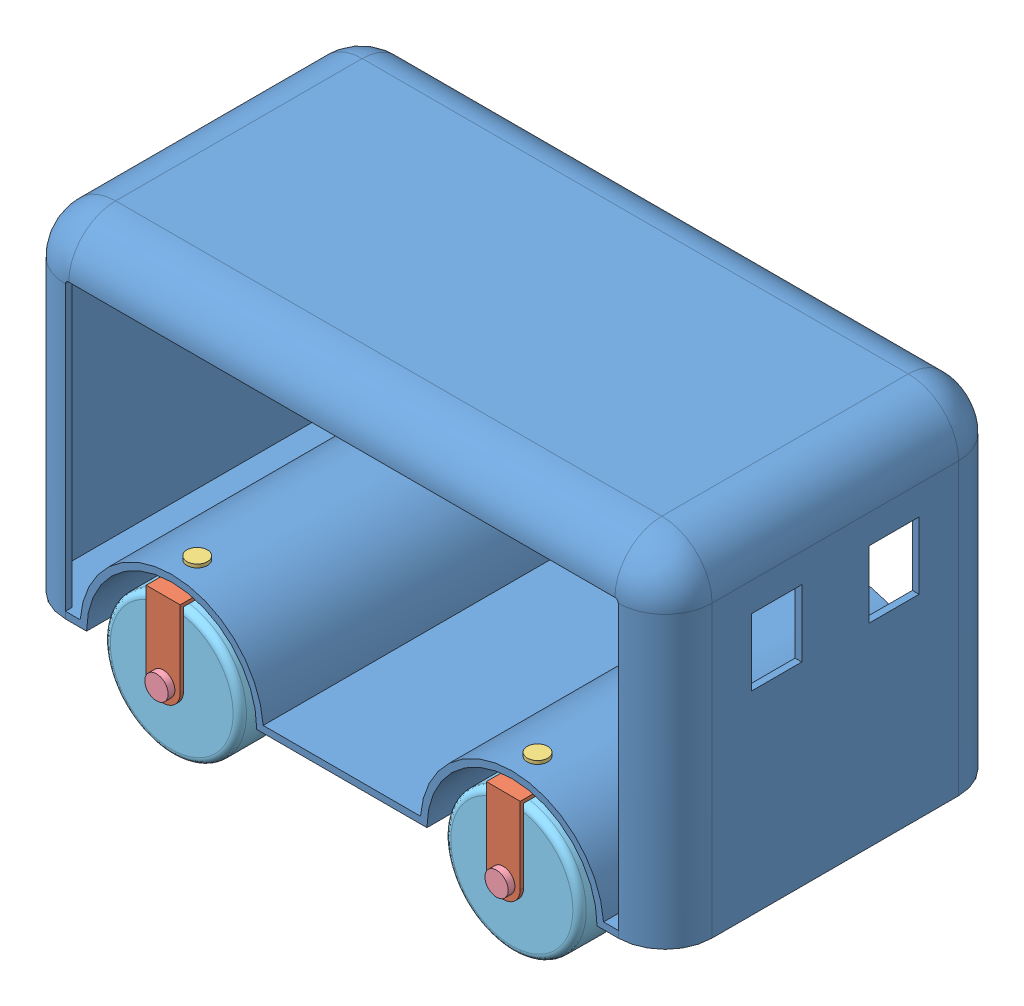
SolidWorks assembly FinalAssem4, configuration Default. Lengths in mm.
Overall size (965.2 647.74 554.88).
21 component instances, 5 part files, 18 mates.
Components (placement in the parent):
- BODY-1: BODY [Default] at (355.0397 333.1063 686.9716) size (965.2 508 508)
- Assem1-1: Assem1 [Default] at (150.2541 268.4552 979.3371) x (-1 0 0) z (0 0 -1) size (50.8 165.1 121.6)
  - 1-1: 1 [Default] at (49.2145 66.9511 76.4655) size (50.8 139.7 101.6)
  - wheelhinge-1: wheelhinge [Default] at (49.2145 188.9511 76.4655) x (0.436076 0 -0.89991) z (0.89991 0 0.436076) size (30.48 35.4 30.48)
  - tyrepin-1: tyrepin [Default] at (49.2145 66.9511 76.4655) x (0.587335 0.809344 0) z (0 0 1) size (35 35 121.6)
- Assem1-2: Assem1 [Default] at (560.2818 268.4552 826.1141) x (0.999982 0 0.005959) z (-0.005959 0 0.999982) size (50.8 165.1 121.6)
  - 1-1: 1 [Default] at (49.2145 66.9511 76.4655) size (50.8 139.7 101.6)
  - wheelhinge-1: wheelhinge [Default] at (49.2145 188.9511 76.4655) x (0.436076 0 -0.89991) z (0.89991 0 0.436076) size (30.48 35.4 30.48)
  - tyrepin-1: tyrepin [Default] at (49.2145 66.9511 76.4655) x (0.587335 0.809344 0) z (0 0 1) size (35 35 121.6)
- Assem1-3: Assem1 [Default] at (51.8252 268.4552 394.606) size (50.8 165.1 121.6)
  - 1-1: 1 [Default] at (49.2145 66.9511 76.4655) size (50.8 139.7 101.6)
  - wheelhinge-1: wheelhinge [Default] at (49.2145 188.9511 76.4655) x (0.436076 0 -0.89991) z (0.89991 0 0.436076) size (30.48 35.4 30.48)
  - tyrepin-1: tyrepin [Default] at (49.2145 66.9511 76.4655) x (0.587335 0.809344 0) z (0 0 1) size (35 35 121.6)
- Assem1-4: Assem1 [Default] at (564.2076 268.4552 391.9569) x (0.998414 0 0.056291) z (-0.056291 0 0.998414) size (50.8 165.1 121.6)
  - 1-1: 1 [Default] at (49.2145 66.9511 76.4655) size (50.8 139.7 101.6)
  - wheelhinge-1: wheelhinge [Default] at (49.2145 188.9511 76.4655) x (0.436076 0 -0.89991) z (0.89991 0 0.436076) size (30.48 35.4 30.48)
  - tyrepin-1: tyrepin [Default] at (49.2145 66.9511 76.4655) x (0.587335 0.809344 0) z (0 0 1) size (35 35 121.6)
- tyre-1: tyre [Default] at (609.0397 335.4063 471.0716) x (-0.175271 -0.984471 -0.009882) z (-0.056291 0 0.998414) size (203.2 203.2 76.2)
- tyre-2: tyre [Default] at (609.0397 335.4063 902.8716) x (0.950972 0.309224 0.005667) z (-0.005959 0 0.999982) size (203.2 203.2 76.2)
- tyre-3: tyre [Default] at (101.0397 335.4063 471.0716) x (-0.805563 -0.592511 0) z (0 0 1) size (203.2 203.2 76.2)
- tyre-4: tyre [Default] at (101.0397 335.4063 902.8716) x (-0.530667 -0.84758 0) z (0 0 1) size (203.2 203.2 76.2)
Mates (geometry in assembly coordinates):
- Concentric1: concentric anti-aligned: cylinder of BODY-1 through (101.0397 366.1063 902.8716) axis (0 1 0) radius 12.7; cylinder of Assem1-1/wheelhinge-1 through (101.0397 470.1063 902.8716) axis (0 -1 0) radius 12.7
- Tangent1: tangent anti-aligned: cylinder of BODY-1 through (101.0397 333.1063 940.9716) axis (0 0 -1) radius 137; plane of Assem1-1/wheelhinge-1 through (101.0397 470.1063 902.8716) normal (0 -1 0)
- Concentric2: concentric anti-aligned: cylinder of BODY-1 through (609.0397 366.1063 902.8716) axis (0 1 0) radius 12.7; cylinder of Assem1-2/wheelhinge-1 through (609.0397 470.1063 902.8716) axis (0 -1 0) radius 12.7
- Tangent2: tangent anti-aligned: cylinder of BODY-1 through (609.0397 333.1063 940.9716) axis (0 0 -1) radius 137; plane of Assem1-2/wheelhinge-1 through (609.0397 470.1063 902.8716) normal (0 -1 0)
- Concentric3: concentric anti-aligned: cylinder of BODY-1 through (101.0397 366.1063 471.0716) axis (0 1 0) radius 12.7; cylinder of Assem1-3/wheelhinge-1 through (101.0397 470.1063 471.0716) axis (0 -1 0) radius 12.7
- Tangent3: tangent anti-aligned: cylinder of BODY-1 through (101.0397 333.1063 940.9716) axis (0 0 -1) radius 137; plane of Assem1-3/wheelhinge-1 through (101.0397 470.1063 471.0716) normal (0 -1 0)
- Concentric4: concentric anti-aligned: cylinder of BODY-1 through (609.0397 366.1063 471.0716) axis (0 1 0) radius 12.7; cylinder of Assem1-4/wheelhinge-1 through (609.0397 470.1063 471.0716) axis (0 -1 0) radius 12.7
- Tangent4: tangent anti-aligned: cylinder of BODY-1 through (609.0397 333.1063 940.9716) axis (0 0 -1) radius 137; plane of Assem1-4/wheelhinge-1 through (609.0397 470.1063 471.0716) normal (0 -1 0)
- Parallel2: parallel aligned: plane of BODY-1 through (762.6397 766.1063 432.9716) normal (0 0 -1); plane of Assem1-3/tyrepin-1 through (101.0397 335.4063 410.2716) normal (0 0 -1)
- Parallel3: parallel aligned: plane of BODY-1 through (762.6397 766.1063 940.9716) normal (0 0 1); plane of Assem1-1/tyrepin-1 through (101.0397 335.4063 963.6716) normal (0 0 1)
- Concentric5: concentric aligned: cylinder of Assem1-4/tyrepin-1 through (606.1801 335.4063 521.791) axis (0.056291 0 -0.998414) radius 12.7; cylinder of tyre-1 through (606.895 335.4063 509.1112) axis (0.056291 0 -0.998414) radius 12.7
- Width1: width anti-aligned: plane of tyre-1 through (611.1843 335.4063 433.032) normal (0.056291 0 -0.998414); plane of Assem1-4/1-1 through (606.895 335.4063 509.1112) normal (-0.056291 0 0.998414); plane of tyre-1 through (535.5386 444.7063 421.0548) normal (-0.056291 0 0.998414); plane of Assem1-4/1-1 through (530.3823 444.7063 512.5096) normal (0.056291 0 -0.998414)
- Concentric6: concentric aligned: cylinder of Assem1-2/tyrepin-1 through (608.7369 335.4063 953.6707) axis (0.005959 0 -0.999982) radius 12.7; cylinder of tyre-2 through (608.8126 335.4063 940.9709) axis (0.005959 0 -0.999982) radius 12.7
- Width2: width anti-aligned: plane of tyre-2 through (608.8126 335.4063 940.9709) normal (-0.005959 0 0.999982); plane of Assem1-2/1-1 through (609.2667 335.4063 864.7723) normal (0.005959 0 -0.999982); plane of tyre-2 through (532.5681 444.7063 948.2167) normal (0.005959 0 -0.999982); plane of Assem1-2/1-1 through (533.1139 444.7063 856.6183) normal (-0.005959 0 0.999982)
- Concentric7: concentric aligned: cylinder of Assem1-3/tyrepin-1 through (101.0397 335.4063 521.8716) axis (0 0 -1) radius 12.7; cylinder of tyre-3 through (101.0397 335.4063 509.1716) axis (0 0 -1) radius 12.7
- Width3: width anti-aligned: plane of tyre-3 through (101.0397 335.4063 432.9716) normal (0 0 -1); plane of Assem1-3/1-1 through (101.0397 335.4063 509.1716) normal (0 0 1); plane of tyre-3 through (24.8397 444.7063 425.2716) normal (0 0 1); plane of Assem1-3/1-1 through (24.8397 444.7063 516.8716) normal (0 0 -1)
- Width4: width anti-aligned: plane of tyre-4 through (101.0397 335.4063 940.9716) normal (0 0 1); plane of Assem1-1/1-1 through (101.0397 335.4063 864.7716) normal (0 0 -1); plane of tyre-4 through (177.2397 444.7063 948.6716) normal (0 0 -1); plane of Assem1-1/1-1 through (177.2397 444.7063 857.0716) normal (0 0 1)
- Concentric8: concentric anti-aligned: cylinder of Assem1-1/tyrepin-1 through (101.0397 335.4063 852.0716) axis (0 0 1) radius 12.7; cylinder of tyre-4 through (101.0397 335.4063 940.9716) axis (0 0 -1) radius 12.7
